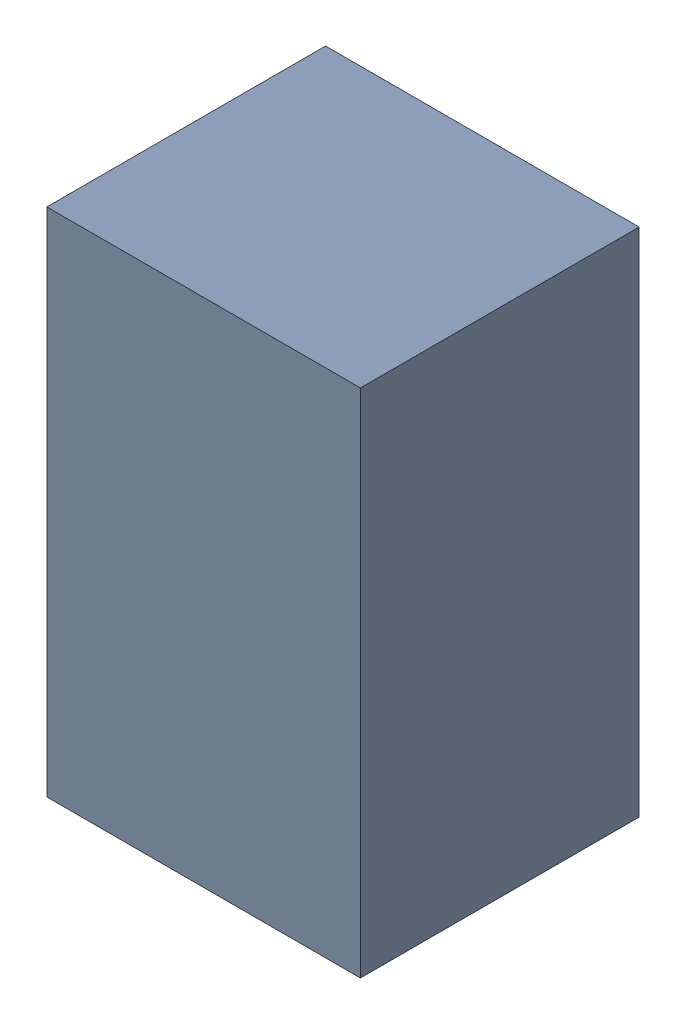
SolidWorks assembly C12., configuration Default. Lengths in mm.
Overall size (1.35 2.2 1.2).
2 component instances, 1 part files, 0 mates.
Components (placement in the parent):
- 407985568-1: 407985568 [Default] at (16.51 24.638 0.0127) size (1.35 2.2 1.2)
  - Extruded_3-1: Extruded_3 [Default] at origin size (1.35 2.2 1.2)
